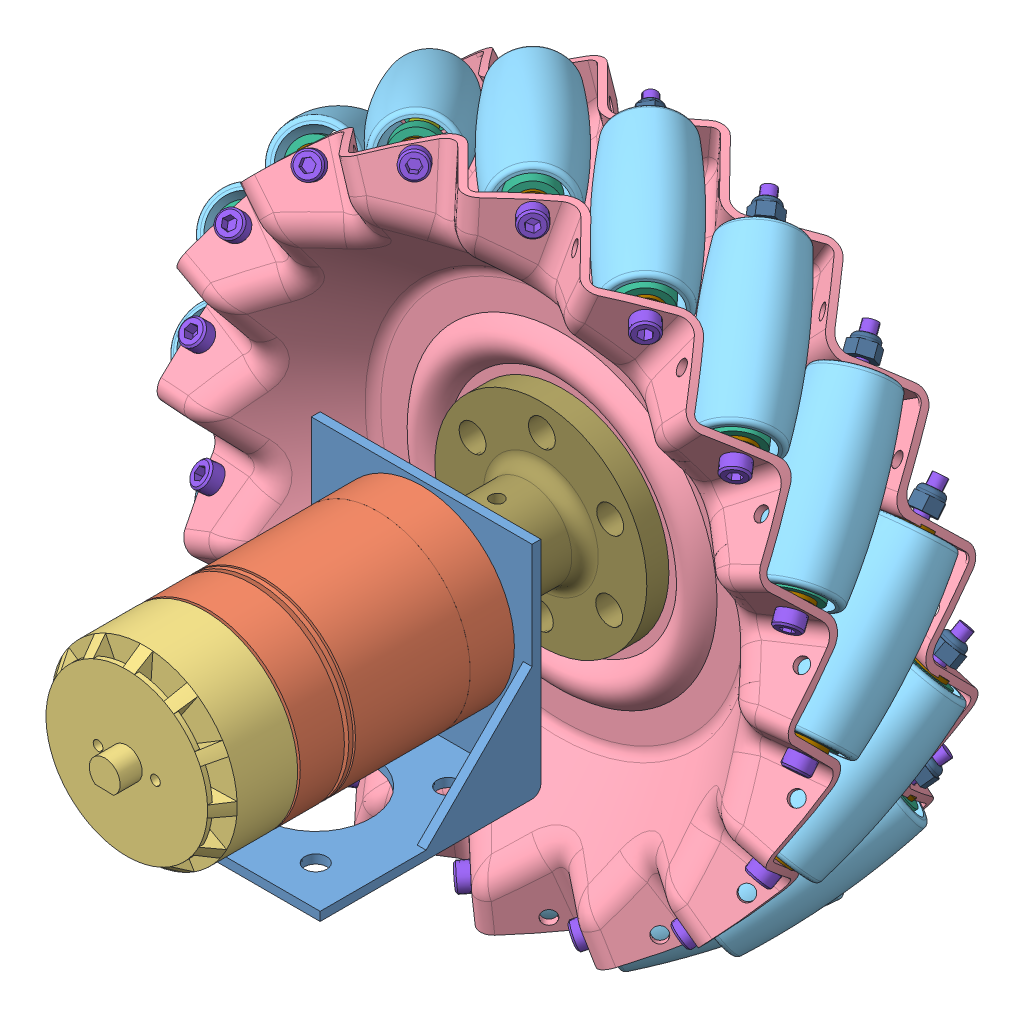
SolidWorks assembly 麦轮加电机（整）, configuration 默认. Lengths in mm.
Overall size (215.08 215.08 133.58).
169 component instances, 13 part files, 5 mates.
Components (placement in the parent):
- 电机固定座（标准）-1: 电机固定座（标准） [默认] at (-18.035 -5.8961 25) size (50 50 50)
- 3508 电机-1: 3508 电机 [默认] at (-3.9401 22.8689 -44.75) x (-1 0 0) z (0 0 1) size (52.13 52.13 98.8)
  - 复件 3508减速^3508 电机-2: 复件 3508减速^3508 电机 [默认] at (-10.9051 0.765 71.75) size (42 42 75.5) (virtual)
  - 复件 3508电机屁股^3508 电机-2: 复件 3508电机屁股^3508 电机 [默认] at (-10.9051 0.765 120.85) x (0.959543 -0.281562 0) z (0 0 1) size (42 42 22.7) (virtual)
- 麦轮（右）-1: 麦轮（右） [默认] at (33.2324 11.0347 -137.4522) x (0.933906 -0.35752 0) z (0 0 1) size (166.55 166.55 53.71)
  - 麦轮钣金-4: 麦轮钣金 [默认] at (-28.4888 0.9465 132.4522) size (142.88 142.88 24.05)
  - 麦轮钣金-5: 麦轮钣金 [默认] at (-28.4888 0.9465 129.2518) x (-0.182456 0.983214 0) z (0 0 -1) size (142.88 142.88 24.05)
  - 滚花橡胶轮组装-1: 滚花橡胶轮组装 [默认] at (-11.7664 74.8711 111.2311) x (-0.611613 0.360957 0.704017) z (0.544848 -0.453042 0.705615) size (18.5 18.5 53)
    - 滚花橡胶轮外-1: 滚花橡胶轮外 [默认] at (-9.896 1.7835 38.5971) size (18.5 18.5 38)
    - 滚花铝柱-1: 滚花铝柱 [默认] at (-9.896 1.7835 38) x (0.787441 0.61639 0) z (-0.61639 0.787441 0) size (13 38 13) (hidden)
    - 轴承5X10X4-1: 轴承5X10X4 [默认] at (-9.896 1.7835 55) x (0.442498 0.896769 0) z (-0.896769 0.442498 0) size (10 4 10)
    - 轴承5X10X4-2: 轴承5X10X4 [默认] at (-9.896 1.7835 21) x (0.442498 0.896769 0) z (-0.896769 0.442498 0) size (10 4 10)
    - 铜管3X5-1: 铜管3X5 [默认] at (-9.896 1.7835 38) x (0.823254 0.567673 0) z (-0.567673 0.823254 0) size (5 38 5)
    - 螺丝-1: 螺丝 [默认] at (-9.896 1.7835 59.6) x (-0.462621 0.886556 0) z (0 0 1) size (5.5 5.5 53)
    - 垫片-1: 垫片 [默认] at (-9.896 1.7835 57) x (1 0 0) z (0 -1 0) size (7 0.8 7)
    - 垫片-2: 垫片 [默认] at (-9.896 1.7835 19) x (0.746862 -0.664979 0) z (0.664979 0.746862 0) size (7 0.8 7)
    - 螺母-1: 螺母 [默认] at (-9.896 1.7835 16.2) x (-0.766894 0.641774 0) z (0 0 -1) size (6.35 5.5 4.25)
  - 滚花橡胶轮组装-2: 滚花橡胶轮组装 [默认] at (27.0215 56.1049 99.7367) x (0.936151 0.121324 -0.330002) z (0.330002 -0.627061 0.705615) size (18.5 18.5 53)
    - 滚花橡胶轮外-1: 滚花橡胶轮外 [默认] at (-9.896 1.7835 38.5971) size (18.5 18.5 38)
    - 滚花铝柱-1: 滚花铝柱 [默认] at (-9.896 1.7835 38) x (0.787441 0.61639 0) z (-0.61639 0.787441 0) size (13 38 13) (hidden)
    - 轴承5X10X4-1: 轴承5X10X4 [默认] at (-9.896 1.7835 55) x (0.442498 0.896769 0) z (-0.896769 0.442498 0) size (10 4 10)
    - 轴承5X10X4-2: 轴承5X10X4 [默认] at (-9.896 1.7835 21) x (0.442498 0.896769 0) z (-0.896769 0.442498 0) size (10 4 10)
    - 铜管3X5-1: 铜管3X5 [默认] at (-9.896 1.7835 38) x (0.823254 0.567673 0) z (-0.567673 0.823254 0) size (5 38 5)
    - 螺丝-1: 螺丝 [默认] at (-9.896 1.7835 59.6) x (-0.462621 0.886556 0) z (0 0 1) size (5.5 5.5 53)
    - 垫片-1: 垫片 [默认] at (-9.896 1.7835 57) x (1 0 0) z (0 -1 0) size (7 0.8 7)
    - 垫片-2: 垫片 [默认] at (-9.896 1.7835 19) x (0.746862 -0.664979 0) z (0.664979 0.746862 0) size (7 0.8 7)
    - 螺母-1: 螺母 [默认] at (-9.896 1.7835 16.2) x (-0.766894 0.641774 0) z (0 0 -1) size (6.35 5.5 4.25)
  - 滚花橡胶轮组装-3: 滚花橡胶轮组装 [默认] at (40.6784 28.3806 97.7508) x (0.648729 -0.507452 -0.567136) z (0.064917 -0.705615 0.705615) size (18.5 18.5 53)
    - 滚花橡胶轮外-1: 滚花橡胶轮外 [默认] at (-9.896 1.7835 38.5971) size (18.5 18.5 38)
    - 滚花铝柱-1: 滚花铝柱 [默认] at (-9.896 1.7835 38) x (0.787441 0.61639 0) z (-0.61639 0.787441 0) size (13 38 13) (hidden)
    - 轴承5X10X4-1: 轴承5X10X4 [默认] at (-9.896 1.7835 55) x (0.442498 0.896769 0) z (-0.896769 0.442498 0) size (10 4 10)
    - 轴承5X10X4-2: 轴承5X10X4 [默认] at (-9.896 1.7835 21) x (0.442498 0.896769 0) z (-0.896769 0.442498 0) size (10 4 10)
    - 铜管3X5-1: 铜管3X5 [默认] at (-9.896 1.7835 38) x (0.823254 0.567673 0) z (-0.567673 0.823254 0) size (5 38 5)
    - 螺丝-1: 螺丝 [默认] at (-9.896 1.7835 59.6) x (-0.462621 0.886556 0) z (0 0 1) size (5.5 5.5 53)
    - 垫片-1: 垫片 [默认] at (-9.896 1.7835 57) x (1 0 0) z (0 -1 0) size (7 0.8 7)
    - 垫片-2: 垫片 [默认] at (-9.896 1.7835 19) x (0.746862 -0.664979 0) z (0.664979 0.746862 0) size (7 0.8 7)
    - 螺母-1: 螺母 [默认] at (-9.896 1.7835 16.2) x (-0.766894 0.641774 0) z (0 0 -1) size (6.35 5.5 4.25)
  - 滚花橡胶轮组装-4: 滚花橡胶轮组装 [默认] at (53.3201 5.2227 104.8515) x (0.974131 -0.083344 0.210052) z (-0.210052 -0.676746 0.705615) size (18.5 18.5 53)
    - 滚花橡胶轮外-1: 滚花橡胶轮外 [默认] at (-9.896 1.7835 38.5971) size (18.5 18.5 38)
    - 滚花铝柱-1: 滚花铝柱 [默认] at (-9.896 1.7835 38) x (0.787441 0.61639 0) z (-0.61639 0.787441 0) size (13 38 13) (hidden)
    - 轴承5X10X4-1: 轴承5X10X4 [默认] at (-9.896 1.7835 55) x (0.442498 0.896769 0) z (-0.896769 0.442498 0) size (10 4 10)
    - 轴承5X10X4-2: 轴承5X10X4 [默认] at (-9.896 1.7835 21) x (0.442498 0.896769 0) z (-0.896769 0.442498 0) size (10 4 10)
    - 铜管3X5-1: 铜管3X5 [默认] at (-9.896 1.7835 38) x (0.823254 0.567673 0) z (-0.567673 0.823254 0) size (5 38 5)
    - 螺丝-1: 螺丝 [默认] at (-9.896 1.7835 59.6) x (-0.462621 0.886556 0) z (0 0 1) size (5.5 5.5 53)
    - 垫片-1: 垫片 [默认] at (-9.896 1.7835 57) x (1 0 0) z (0 -1 0) size (7 0.8 7)
    - 垫片-2: 垫片 [默认] at (-9.896 1.7835 19) x (0.746862 -0.664979 0) z (0.664979 0.746862 0) size (7 0.8 7)
    - 螺母-1: 螺母 [默认] at (-9.896 1.7835 16.2) x (-0.766894 0.641774 0) z (0 0 -1) size (6.35 5.5 4.25)
  - 滚花橡胶轮组装-6: 滚花橡胶轮组装 [默认] at (49.4638 -23.6017 107.4914) x (0.879664 -0.144722 0.453042) z (-0.453042 -0.544848 0.705615) size (18.5 18.5 53)
    - 滚花橡胶轮外-1: 滚花橡胶轮外 [默认] at (-9.896 1.7835 38.5971) size (18.5 18.5 38)
    - 滚花铝柱-1: 滚花铝柱 [默认] at (-9.896 1.7835 38) x (0.787441 0.61639 0) z (-0.61639 0.787441 0) size (13 38 13) (hidden)
    - 轴承5X10X4-1: 轴承5X10X4 [默认] at (-9.896 1.7835 55) x (0.442498 0.896769 0) z (-0.896769 0.442498 0) size (10 4 10)
    - 轴承5X10X4-2: 轴承5X10X4 [默认] at (-9.896 1.7835 21) x (0.442498 0.896769 0) z (-0.896769 0.442498 0) size (10 4 10)
    - 铜管3X5-1: 铜管3X5 [默认] at (-9.896 1.7835 38) x (0.823254 0.567673 0) z (-0.567673 0.823254 0) size (5 38 5)
    - 螺丝-1: 螺丝 [默认] at (-9.896 1.7835 59.6) x (-0.462621 0.886556 0) z (0 0 1) size (5.5 5.5 53)
    - 垫片-1: 垫片 [默认] at (-9.896 1.7835 57) x (1 0 0) z (0 -1 0) size (7 0.8 7)
    - 垫片-2: 垫片 [默认] at (-9.896 1.7835 19) x (0.746862 -0.664979 0) z (0.664979 0.746862 0) size (7 0.8 7)
    - 螺母-1: 螺母 [默认] at (-9.896 1.7835 16.2) x (-0.766894 0.641774 0) z (0 0 -1) size (6.35 5.5 4.25)
  - 滚花橡胶轮组装-7: 滚花橡胶轮组装 [默认] at (34.7976 -48.3203 109.5966) x (0.769464 -0.121324 0.627061) z (-0.627061 -0.330002 0.705615) size (18.5 18.5 53)
    - 滚花橡胶轮外-1: 滚花橡胶轮外 [默认] at (-9.896 1.7835 38.5971) size (18.5 18.5 38)
    - 滚花铝柱-1: 滚花铝柱 [默认] at (-9.896 1.7835 38) x (0.787441 0.61639 0) z (-0.61639 0.787441 0) size (13 38 13) (hidden)
    - 轴承5X10X4-1: 轴承5X10X4 [默认] at (-9.896 1.7835 55) x (0.442498 0.896769 0) z (-0.896769 0.442498 0) size (10 4 10)
    - 轴承5X10X4-2: 轴承5X10X4 [默认] at (-9.896 1.7835 21) x (0.442498 0.896769 0) z (-0.896769 0.442498 0) size (10 4 10)
    - 铜管3X5-1: 铜管3X5 [默认] at (-9.896 1.7835 38) x (0.823254 0.567673 0) z (-0.567673 0.823254 0) size (5 38 5)
    - 螺丝-1: 螺丝 [默认] at (-9.896 1.7835 59.6) x (-0.462621 0.886556 0) z (0 0 1) size (5.5 5.5 53)
    - 垫片-1: 垫片 [默认] at (-9.896 1.7835 57) x (1 0 0) z (0 -1 0) size (7 0.8 7)
    - 垫片-2: 垫片 [默认] at (-9.896 1.7835 19) x (0.746862 -0.664979 0) z (0.664979 0.746862 0) size (7 0.8 7)
    - 螺母-1: 螺母 [默认] at (-9.896 1.7835 16.2) x (-0.766894 0.641774 0) z (0 0 -1) size (6.35 5.5 4.25)
  - 滚花橡胶轮组装-8: 滚花橡胶轮组装 [默认] at (11.9043 -65.198 110.9878) x (0.708086 -0.026856 0.705615) z (-0.705615 -0.064917 0.705615) size (18.5 18.5 53)
    - 滚花橡胶轮外-1: 滚花橡胶轮外 [默认] at (-9.896 1.7835 38.5971) size (18.5 18.5 38)
    - 滚花铝柱-1: 滚花铝柱 [默认] at (-9.896 1.7835 38) x (0.787441 0.61639 0) z (-0.61639 0.787441 0) size (13 38 13) (hidden)
    - 轴承5X10X4-1: 轴承5X10X4 [默认] at (-9.896 1.7835 55) x (0.442498 0.896769 0) z (-0.896769 0.442498 0) size (10 4 10)
    - 轴承5X10X4-2: 轴承5X10X4 [默认] at (-9.896 1.7835 21) x (0.442498 0.896769 0) z (-0.896769 0.442498 0) size (10 4 10)
    - 铜管3X5-1: 铜管3X5 [默认] at (-9.896 1.7835 38) x (0.823254 0.567673 0) z (-0.567673 0.823254 0) size (5 38 5)
    - 螺丝-1: 螺丝 [默认] at (-9.896 1.7835 59.6) x (-0.462621 0.886556 0) z (0 0 1) size (5.5 5.5 53)
    - 垫片-1: 垫片 [默认] at (-9.896 1.7835 57) x (1 0 0) z (0 -1 0) size (7 0.8 7)
    - 垫片-2: 垫片 [默认] at (-9.896 1.7835 19) x (0.746862 -0.664979 0) z (0.664979 0.746862 0) size (7 0.8 7)
    - 螺母-1: 螺母 [默认] at (-9.896 1.7835 16.2) x (-0.766894 0.641774 0) z (0 0 -1) size (6.35 5.5 4.25)
  - 滚花橡胶轮组装-9: 滚花橡胶轮组装 [默认] at (-20.4065 -80.021 108.2514) x (0.291286 -0.803832 0.518658) z (-0.676746 0.210052 0.705615) size (18.5 18.5 53)
    - 滚花橡胶轮外-1: 滚花橡胶轮外 [默认] at (-9.896 1.7835 38.5971) size (18.5 18.5 38)
    - 滚花铝柱-1: 滚花铝柱 [默认] at (-9.896 1.7835 38) x (0.787441 0.61639 0) z (-0.61639 0.787441 0) size (13 38 13) (hidden)
    - 轴承5X10X4-1: 轴承5X10X4 [默认] at (-9.896 1.7835 55) x (0.442498 0.896769 0) z (-0.896769 0.442498 0) size (10 4 10)
    - 轴承5X10X4-2: 轴承5X10X4 [默认] at (-9.896 1.7835 21) x (0.442498 0.896769 0) z (-0.896769 0.442498 0) size (10 4 10)
    - 铜管3X5-1: 铜管3X5 [默认] at (-9.896 1.7835 38) x (0.823254 0.567673 0) z (-0.567673 0.823254 0) size (5 38 5)
    - 螺丝-1: 螺丝 [默认] at (-9.896 1.7835 59.6) x (-0.462621 0.886556 0) z (0 0 1) size (5.5 5.5 53)
    - 垫片-1: 垫片 [默认] at (-9.896 1.7835 57) x (1 0 0) z (0 -1 0) size (7 0.8 7)
    - 垫片-2: 垫片 [默认] at (-9.896 1.7835 19) x (0.746862 -0.664979 0) z (0.664979 0.746862 0) size (7 0.8 7)
    - 螺母-1: 螺母 [默认] at (-9.896 1.7835 16.2) x (-0.766894 0.641774 0) z (0 0 -1) size (6.35 5.5 4.25)
  - 滚花橡胶轮组装-10: 滚花橡胶轮组装 [默认] at (-46.4094 -74.3284 110.8897) x (0.497758 -0.502453 0.70695) z (-0.544848 0.453042 0.705615) size (18.5 18.5 53)
    - 滚花橡胶轮外-1: 滚花橡胶轮外 [默认] at (-9.896 1.7835 38.5971) size (18.5 18.5 38)
    - 滚花铝柱-1: 滚花铝柱 [默认] at (-9.896 1.7835 38) x (0.787441 0.61639 0) z (-0.61639 0.787441 0) size (13 38 13) (hidden)
    - 轴承5X10X4-1: 轴承5X10X4 [默认] at (-9.896 1.7835 55) x (0.442498 0.896769 0) z (-0.896769 0.442498 0) size (10 4 10)
    - 轴承5X10X4-2: 轴承5X10X4 [默认] at (-9.896 1.7835 21) x (0.442498 0.896769 0) z (-0.896769 0.442498 0) size (10 4 10)
    - 铜管3X5-1: 铜管3X5 [默认] at (-9.896 1.7835 38) x (0.823254 0.567673 0) z (-0.567673 0.823254 0) size (5 38 5)
    - 螺丝-1: 螺丝 [默认] at (-9.896 1.7835 59.6) x (-0.462621 0.886556 0) z (0 0 1) size (5.5 5.5 53)
    - 垫片-1: 垫片 [默认] at (-9.896 1.7835 57) x (1 0 0) z (0 -1 0) size (7 0.8 7)
    - 垫片-2: 垫片 [默认] at (-9.896 1.7835 19) x (0.746862 -0.664979 0) z (0.664979 0.746862 0) size (7 0.8 7)
    - 螺母-1: 螺母 [默认] at (-9.896 1.7835 16.2) x (-0.766894 0.641774 0) z (0 0 -1) size (6.35 5.5 4.25)
  - 滚花橡胶轮组装-18: 滚花橡胶轮组装 [默认] at (-41.329 75.6433 111.2311) x (-0.703189 0.099427 0.704017) z (0.676746 -0.210052 0.705615) size (18.5 18.5 53)
    - 滚花橡胶轮外-1: 滚花橡胶轮外 [默认] at (-9.896 1.7835 38.5971) size (18.5 18.5 38)
    - 滚花铝柱-1: 滚花铝柱 [默认] at (-9.896 1.7835 38) x (0.787441 0.61639 0) z (-0.61639 0.787441 0) size (13 38 13) (hidden)
    - 轴承5X10X4-1: 轴承5X10X4 [默认] at (-9.896 1.7835 55) x (0.442498 0.896769 0) z (-0.896769 0.442498 0) size (10 4 10)
    - 轴承5X10X4-2: 轴承5X10X4 [默认] at (-9.896 1.7835 21) x (0.442498 0.896769 0) z (-0.896769 0.442498 0) size (10 4 10)
    - 铜管3X5-1: 铜管3X5 [默认] at (-9.896 1.7835 38) x (0.823254 0.567673 0) z (-0.567673 0.823254 0) size (5 38 5)
    - 螺丝-1: 螺丝 [默认] at (-9.896 1.7835 59.6) x (-0.462621 0.886556 0) z (0 0 1) size (5.5 5.5 53)
    - 垫片-1: 垫片 [默认] at (-9.896 1.7835 57) x (1 0 0) z (0 -1 0) size (7 0.8 7)
    - 垫片-2: 垫片 [默认] at (-9.896 1.7835 19) x (0.746862 -0.664979 0) z (0.664979 0.746862 0) size (7 0.8 7)
    - 螺母-1: 螺母 [默认] at (-9.896 1.7835 16.2) x (-0.766894 0.641774 0) z (0 0 -1) size (6.35 5.5 4.25)
  - 滚花橡胶轮组装-19: 滚花橡胶轮组装 [默认] at (-68.9368 65.0436 111.2311) x (-0.687711 -0.17724 0.704017) z (0.705615 0.064917 0.705615) size (18.5 18.5 53)
    - 滚花橡胶轮外-1: 滚花橡胶轮外 [默认] at (-9.896 1.7835 38.5971) size (18.5 18.5 38)
    - 滚花铝柱-1: 滚花铝柱 [默认] at (-9.896 1.7835 38) x (0.787441 0.61639 0) z (-0.61639 0.787441 0) size (13 38 13) (hidden)
    - 轴承5X10X4-1: 轴承5X10X4 [默认] at (-9.896 1.7835 55) x (0.442498 0.896769 0) z (-0.896769 0.442498 0) size (10 4 10)
    - 轴承5X10X4-2: 轴承5X10X4 [默认] at (-9.896 1.7835 21) x (0.442498 0.896769 0) z (-0.896769 0.442498 0) size (10 4 10)
    - 铜管3X5-1: 铜管3X5 [默认] at (-9.896 1.7835 38) x (0.823254 0.567673 0) z (-0.567673 0.823254 0) size (5 38 5)
    - 螺丝-1: 螺丝 [默认] at (-9.896 1.7835 59.6) x (-0.462621 0.886556 0) z (0 0 1) size (5.5 5.5 53)
    - 垫片-1: 垫片 [默认] at (-9.896 1.7835 57) x (1 0 0) z (0 -1 0) size (7 0.8 7)
    - 垫片-2: 垫片 [默认] at (-9.896 1.7835 19) x (0.746862 -0.664979 0) z (0.664979 0.746862 0) size (7 0.8 7)
    - 螺母-1: 螺母 [默认] at (-9.896 1.7835 16.2) x (-0.766894 0.641774 0) z (0 0 -1) size (6.35 5.5 4.25)
  - 滚花橡胶轮组装-20: 滚花橡胶轮组装 [默认] at (-90.3868 44.6856 111.2311) x (-0.567535 -0.426924 0.704017) z (0.627061 0.330002 0.705615) size (18.5 18.5 53)
    - 滚花橡胶轮外-1: 滚花橡胶轮外 [默认] at (-9.896 1.7835 38.5971) size (18.5 18.5 38)
    - 滚花铝柱-1: 滚花铝柱 [默认] at (-9.896 1.7835 38) x (0.787441 0.61639 0) z (-0.61639 0.787441 0) size (13 38 13) (hidden)
    - 轴承5X10X4-1: 轴承5X10X4 [默认] at (-9.896 1.7835 55) x (0.442498 0.896769 0) z (-0.896769 0.442498 0) size (10 4 10)
    - 轴承5X10X4-2: 轴承5X10X4 [默认] at (-9.896 1.7835 21) x (0.442498 0.896769 0) z (-0.896769 0.442498 0) size (10 4 10)
    - 铜管3X5-1: 铜管3X5 [默认] at (-9.896 1.7835 38) x (0.823254 0.567673 0) z (-0.567673 0.823254 0) size (5 38 5)
    - 螺丝-1: 螺丝 [默认] at (-9.896 1.7835 59.6) x (-0.462621 0.886556 0) z (0 0 1) size (5.5 5.5 53)
    - 垫片-1: 垫片 [默认] at (-9.896 1.7835 57) x (1 0 0) z (0 -1 0) size (7 0.8 7)
    - 垫片-2: 垫片 [默认] at (-9.896 1.7835 19) x (0.746862 -0.664979 0) z (0.664979 0.746862 0) size (7 0.8 7)
    - 螺母-1: 螺母 [默认] at (-9.896 1.7835 16.2) x (-0.766894 0.641774 0) z (0 0 -1) size (6.35 5.5 4.25)
  - 滚花橡胶轮组装-21: 滚花橡胶轮组装 [默认] at (-102.4133 17.6688 111.2311) x (-0.360957 -0.611613 0.704017) z (0.453042 0.544848 0.705615) size (18.5 18.5 53)
    - 滚花橡胶轮外-1: 滚花橡胶轮外 [默认] at (-9.896 1.7835 38.5971) size (18.5 18.5 38)
    - 滚花铝柱-1: 滚花铝柱 [默认] at (-9.896 1.7835 38) x (0.787441 0.61639 0) z (-0.61639 0.787441 0) size (13 38 13) (hidden)
    - 轴承5X10X4-1: 轴承5X10X4 [默认] at (-9.896 1.7835 55) x (0.442498 0.896769 0) z (-0.896769 0.442498 0) size (10 4 10)
    - 轴承5X10X4-2: 轴承5X10X4 [默认] at (-9.896 1.7835 21) x (0.442498 0.896769 0) z (-0.896769 0.442498 0) size (10 4 10)
    - 铜管3X5-1: 铜管3X5 [默认] at (-9.896 1.7835 38) x (0.823254 0.567673 0) z (-0.567673 0.823254 0) size (5 38 5)
    - 螺丝-1: 螺丝 [默认] at (-9.896 1.7835 59.6) x (-0.462621 0.886556 0) z (0 0 1) size (5.5 5.5 53)
    - 垫片-1: 垫片 [默认] at (-9.896 1.7835 57) x (1 0 0) z (0 -1 0) size (7 0.8 7)
    - 垫片-2: 垫片 [默认] at (-9.896 1.7835 19) x (0.746862 -0.664979 0) z (0.664979 0.746862 0) size (7 0.8 7)
    - 螺母-1: 螺母 [默认] at (-9.896 1.7835 16.2) x (-0.766894 0.641774 0) z (0 0 -1) size (6.35 5.5 4.25)
  - 滚花橡胶轮组装-22: 滚花橡胶轮组装 [默认] at (-103.1855 -11.8938 111.2311) x (-0.099427 -0.703189 0.704017) z (0.210052 0.676746 0.705615) size (18.5 18.5 53)
    - 滚花橡胶轮外-1: 滚花橡胶轮外 [默认] at (-9.896 1.7835 38.5971) size (18.5 18.5 38)
    - 滚花铝柱-1: 滚花铝柱 [默认] at (-9.896 1.7835 38) x (0.787441 0.61639 0) z (-0.61639 0.787441 0) size (13 38 13) (hidden)
    - 轴承5X10X4-1: 轴承5X10X4 [默认] at (-9.896 1.7835 55) x (0.442498 0.896769 0) z (-0.896769 0.442498 0) size (10 4 10)
    - 轴承5X10X4-2: 轴承5X10X4 [默认] at (-9.896 1.7835 21) x (0.442498 0.896769 0) z (-0.896769 0.442498 0) size (10 4 10)
    - 铜管3X5-1: 铜管3X5 [默认] at (-9.896 1.7835 38) x (0.823254 0.567673 0) z (-0.567673 0.823254 0) size (5 38 5)
    - 螺丝-1: 螺丝 [默认] at (-9.896 1.7835 59.6) x (-0.462621 0.886556 0) z (0 0 1) size (5.5 5.5 53)
    - 垫片-1: 垫片 [默认] at (-9.896 1.7835 57) x (1 0 0) z (0 -1 0) size (7 0.8 7)
    - 垫片-2: 垫片 [默认] at (-9.896 1.7835 19) x (0.746862 -0.664979 0) z (0.664979 0.746862 0) size (7 0.8 7)
    - 螺母-1: 螺母 [默认] at (-9.896 1.7835 16.2) x (-0.766894 0.641774 0) z (0 0 -1) size (6.35 5.5 4.25)
  - 滚花橡胶轮组装-23: 滚花橡胶轮组装 [默认] at (-92.5858 -39.5016 111.2311) x (0.17724 -0.687711 0.704017) z (-0.064917 0.705615 0.705615) size (18.5 18.5 53)
    - 滚花橡胶轮外-1: 滚花橡胶轮外 [默认] at (-9.896 1.7835 38.5971) size (18.5 18.5 38)
    - 滚花铝柱-1: 滚花铝柱 [默认] at (-9.896 1.7835 38) x (0.787441 0.61639 0) z (-0.61639 0.787441 0) size (13 38 13) (hidden)
    - 轴承5X10X4-1: 轴承5X10X4 [默认] at (-9.896 1.7835 55) x (0.442498 0.896769 0) z (-0.896769 0.442498 0) size (10 4 10)
    - 轴承5X10X4-2: 轴承5X10X4 [默认] at (-9.896 1.7835 21) x (0.442498 0.896769 0) z (-0.896769 0.442498 0) size (10 4 10)
    - 铜管3X5-1: 铜管3X5 [默认] at (-9.896 1.7835 38) x (0.823254 0.567673 0) z (-0.567673 0.823254 0) size (5 38 5)
    - 螺丝-1: 螺丝 [默认] at (-9.896 1.7835 59.6) x (-0.462621 0.886556 0) z (0 0 1) size (5.5 5.5 53)
    - 垫片-1: 垫片 [默认] at (-9.896 1.7835 57) x (1 0 0) z (0 -1 0) size (7 0.8 7)
    - 垫片-2: 垫片 [默认] at (-9.896 1.7835 19) x (0.746862 -0.664979 0) z (0.664979 0.746862 0) size (7 0.8 7)
    - 螺母-1: 螺母 [默认] at (-9.896 1.7835 16.2) x (-0.766894 0.641774 0) z (0 0 -1) size (6.35 5.5 4.25)
  - 滚花橡胶轮组装-24: 滚花橡胶轮组装 [默认] at (-72.2279 -60.9516 111.2311) x (0.426924 -0.567535 0.704017) z (-0.330002 0.627061 0.705615) size (18.5 18.5 53)
    - 滚花橡胶轮外-1: 滚花橡胶轮外 [默认] at (-9.896 1.7835 38.5971) size (18.5 18.5 38)
    - 滚花铝柱-1: 滚花铝柱 [默认] at (-9.896 1.7835 38) x (0.787441 0.61639 0) z (-0.61639 0.787441 0) size (13 38 13) (hidden)
    - 轴承5X10X4-1: 轴承5X10X4 [默认] at (-9.896 1.7835 55) x (0.442498 0.896769 0) z (-0.896769 0.442498 0) size (10 4 10)
    - 轴承5X10X4-2: 轴承5X10X4 [默认] at (-9.896 1.7835 21) x (0.442498 0.896769 0) z (-0.896769 0.442498 0) size (10 4 10)
    - 铜管3X5-1: 铜管3X5 [默认] at (-9.896 1.7835 38) x (0.823254 0.567673 0) z (-0.567673 0.823254 0) size (5 38 5)
    - 螺丝-1: 螺丝 [默认] at (-9.896 1.7835 59.6) x (-0.462621 0.886556 0) z (0 0 1) size (5.5 5.5 53)
    - 垫片-1: 垫片 [默认] at (-9.896 1.7835 57) x (1 0 0) z (0 -1 0) size (7 0.8 7)
    - 垫片-2: 垫片 [默认] at (-9.896 1.7835 19) x (0.746862 -0.664979 0) z (0.664979 0.746862 0) size (7 0.8 7)
    - 螺母-1: 螺母 [默认] at (-9.896 1.7835 16.2) x (-0.766894 0.641774 0) z (0 0 -1) size (6.35 5.5 4.25)
  - 电机固定器 2-1: 电机固定器 2 [默认] at (-28.4888 0.9465 126.2518) x (0 0 1) z (-0.768427 0.639938 0) size (3 48 48)
  - 电机固定器1-1: 电机固定器1 [默认] at (-28.4888 0.9465 137.4522) x (0 0 -1) z (0.938416 0.345508 0) size (26 48 48)
Mates (geometry in assembly coordinates):
- 同心1: concentric aligned: circle of 3508 电机-1/复件 3508减速^3508 电机-2; circle of 麦轮（右）-1/电机固定器1-1
- 同心2: concentric anti-aligned: cylinder of 3508 电机-1/复件 3508减速^3508 电机-2 through (6.965 43.1039 21.7189) axis (0 -1 0) radius 1.5; cylinder of 麦轮（右）-1/电机固定器1-1 through (6.965 -2.202 21.7189) axis (0 1 0) radius 1.5
- 同心3: concentric anti-aligned: circle of 电机固定座（标准）-1; circle of 3508 电机-1/复件 3508减速^3508 电机-2
- 同心4: concentric anti-aligned: circle of 电机固定座（标准）-1; circle of 3508 电机-1/复件 3508减速^3508 电机-2
- 重合6: coincident anti-aligned: plane of 电机固定座（标准）-1 through (31.965 -3.8961 27) normal (0 0 1); plane of 3508 电机-1/复件 3508减速^3508 电机-2 through (6.965 22.1039 27) normal (0 0 -1)
